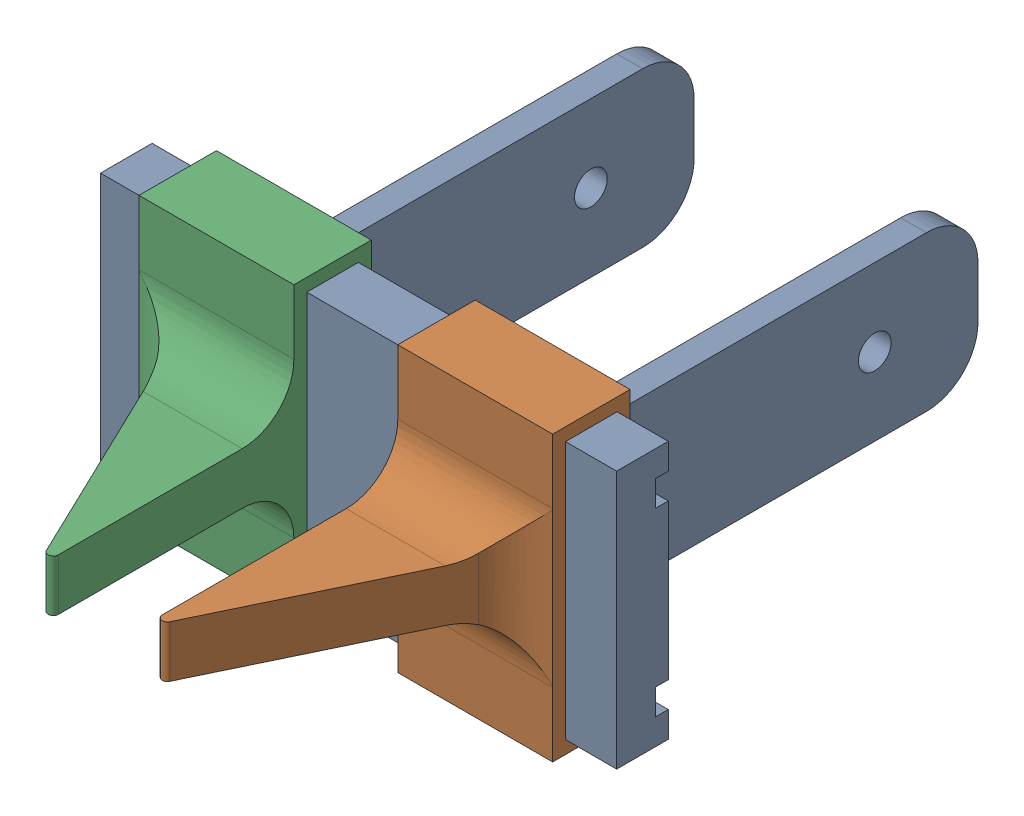
SolidWorks assembly Claw_asm, configuration Default. Lengths in mm.
Overall size (100 55 139.11).
3 component instances, 2 part files, 4 mates.
Components (placement in the parent):
- Claw_track-1: Claw_track [Default] at (-26.3043 11.2167 54.6289) size (100 50 90)
- claw_arm-1: claw_arm [Default] at (63.7933 53.7167 57.1289) x (0 0 1) z (-1 0 0) size (61.61 55 30.87)
- claw_arm-2: claw_arm [Default] at (-16.3383 18.7167 57.1289) x (0 0 1) z (1 0 0) size (61.61 55 30.87)
Mates (geometry in assembly coordinates):
- Coincident1: coincident anti-aligned: plane of Claw_track-1 through (-26.3043 11.2167 64.6289) normal (0 0 1); plane of claw_arm-1 through (33.7933 11.2167 64.6289) normal (0 0 -1)
- Coincident3: coincident anti-aligned: plane of Claw_track-1 through (-26.3043 11.2167 64.6289) normal (0 -1 0); plane of claw_arm-1 through (33.7933 11.2167 54.6289) normal (0 1 0)
- Coincident6: coincident anti-aligned: plane of Claw_track-1 through (-26.3043 11.2167 64.6289) normal (0 0 1); plane of claw_arm-2 through (13.6617 61.2167 64.6289) normal (0 0 -1)
- Coincident7: coincident anti-aligned: plane of Claw_track-1 through (-26.3043 61.2167 64.6289) normal (0 1 0); plane of claw_arm-2 through (13.6617 61.2167 54.6289) normal (0 -1 0)
